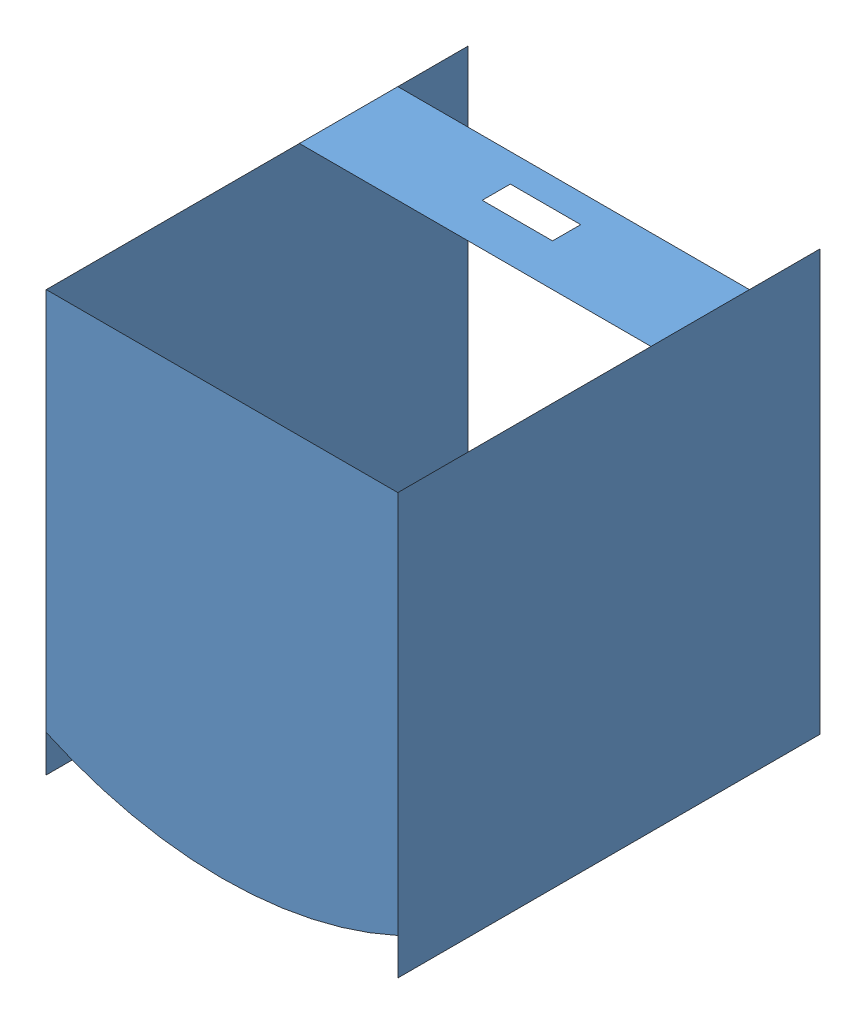
SolidWorks assembly 9 choice, configuration 기본. Lengths in mm.
Overall size (6359.65 7628.69 8445.5).
13 component instances, 12 part files, 0 mates.
Components (placement in the parent):
- ___1-1: ___1 [기본] at (5148.7762 -19916.4414 4445)
- ___6-1: ___6 [기본] at (3175 3120.8391 1270)
- ___5-1: ___5 [기본] at (2746.3775 3141.3024 1270) x (0.995452 -0.095267 0) z (0 0 1)
- ___4-1: ___4 [기본] at (2321.6539 3202.5064 1270) x (0.981848 -0.189668 0) z (0 0 1)
- ___3-1: ___3 [기본] at (1904.6928 3303.8943 1270) x (0.959313 -0.282343 0) z (0 0 1)
- ___7-1: ___7 [기본] at (3603.6225 3141.3024 1270) x (0.995452 0.095267 0) z (0 0 1)
- ___8-1: ___8 [기본] at (4026.8041 3202.2088 1270) x (0.981914 0.189325 0) z (0 0 1)
- ___9-1: ___9 [기본] at (4443.8005 3303.4511 1270) x (0.959412 0.282008 0) z (0 0 1)
- ___10-1: ___10 [기본] at (4847.7974 3443.3748 1270) x (0.928312 0.371802 0) z (0 0 1)
- ___2-1: ___2 [기본] at (1499.2871 3444.5437 1270) x (0.928052 -0.37245 0) z (0 0 1)
- 9 choice-1-1: 9 choice-1 [기본] at origin size (6350 7620.05 7620)
  - 9 choice-1-1: 9 choice-1 [기본] at origin size (6350 7620.05 7620)
- 9 choice-1: 9 choice [기본] at origin size (6359.65 7628.69 8445.5)
